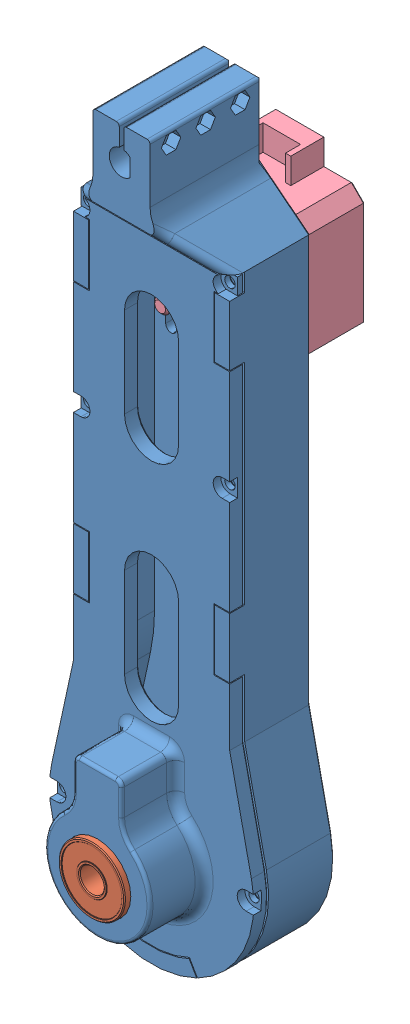
SolidWorks assembly 5to1LastAssem, configuration Default. Lengths in mm.
Overall size (68 247 70).
5 component instances, 4 part files, 8 mates.
Components (placement in the parent):
- 5to1LastSegment-1: 5to1LastSegment [Default] at origin size (68 247 45)
- 608_Bearing-1: 608_Bearing [Default] at (0 -150 5.5) size (22 22 7)
- GT2_80t_TimingBeltPulley-1: GT2_80t_TimingBeltPulley [Default] at (0 -150 15.9585) size (52.13 52.13 10.3)
- NEMA-17_38mm-1: NEMA-17_38mm [23mm] at (-0.1636 3.8774 -23) size (42.3 50.8 47)
- 608_Bearing-2: 608_Bearing [Default] at (0 -150 43.5) x (0.828426 -0.560098 0) z (0 0 1) size (22 22 7)
Mates (geometry in assembly coordinates):
- Coincident1: coincident anti-aligned: plane of 5to1LastSegment-1 through (0 0 0) normal (0 0 -1); plane of NEMA-17_38mm-1 through (-0.1636 3.8774 0) normal (0 0 1)
- Concentric3: concentric aligned: cylinder of 5to1LastSegment-1 through (0 -150 5) axis (0 0 -1) radius 11.1; cylinder of 608_Bearing-1 through (0 -150 9) axis (0 0 -1) radius 11
- Coincident2: coincident anti-aligned: plane of 5to1LastSegment-1 through (0 -150 2) normal (0 0 1); plane of 608_Bearing-1 through (0 -150 2) normal (0 0 -1)
- Concentric6: concentric anti-aligned: cylinder of 5to1LastSegment-1 through (0 -150 40) axis (0 0 1) radius 11.1; cylinder of 608_Bearing-2 through (0 -150 47) axis (0 0 -1) radius 11
- Coincident5: coincident anti-aligned: plane of 5to1LastSegment-1 through (0 -150 40) normal (0 0 1); plane of 608_Bearing-2 through (0 -150 40) normal (0 0 -1)
- Concentric7: concentric aligned: cylinder of 608_Bearing-2 through (0 -150 47) axis (0 0 -1) radius 4; cylinder of long8mmRod-1 through (0 -150 46.75) axis (0 0 -1) radius 4
- Coincident8: coincident aligned: plane of 608_Bearing-2 through (0 -150 46.75) normal (0 0 1); plane of long8mmRod-1 through (0 -150 46.75) normal (0 0 1)
- Concentric8: concentric anti-aligned: cylinder of GT2_80t_TimingBeltPulley-1 through (0 -150 11.5585) axis (0 0 1) radius 4; cylinder of long8mmRod-1 through (0 -150 46.75) axis (0 0 -1) radius 4
